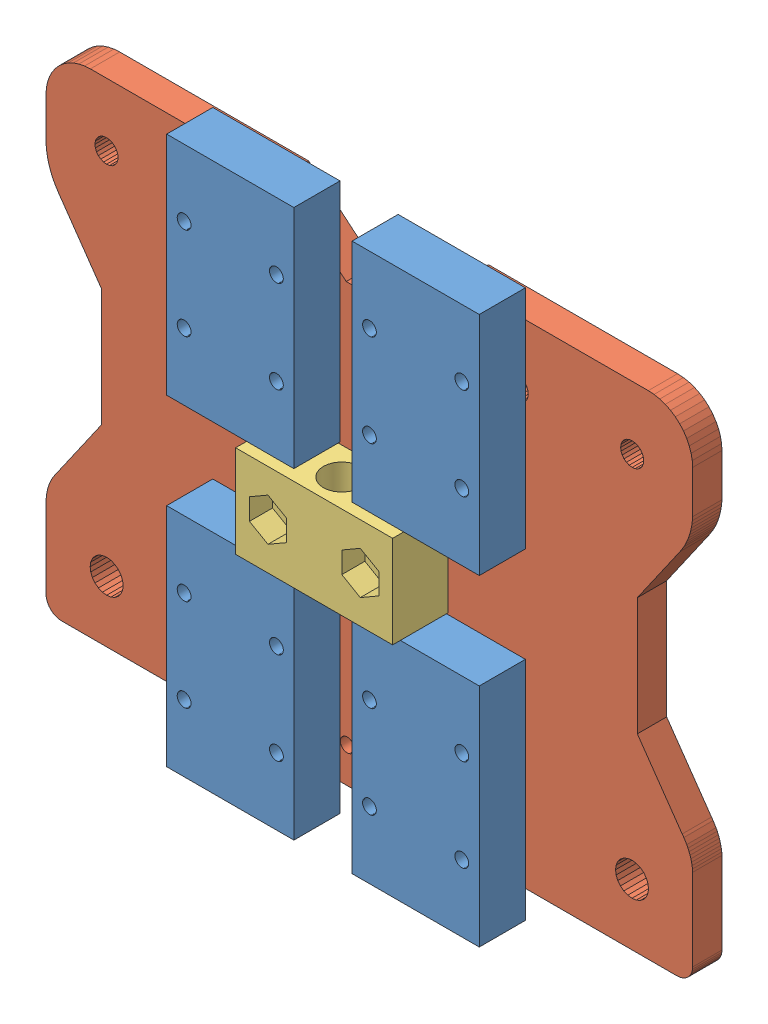
SolidWorks assembly Assem1, configuration Default. Lengths in mm.
Overall size (140.05 118.72 18.4).
6 component instances, 3 part files, 16 mates.
Components (placement in the parent):
- Mg12 block-1: Mg12 block [Default] at (164.5999 -6 6.6764) x (1 0 -0.000519) z (0.000519 0 1) size (27.56 49 10)
- for sliders-1: for sliders [Default] at (126.4849 583.1079 0.3462) x (0 -1 0) z (0.000519 0 1) size (106.72 140.05 6.35)
- Mg12 block-2: Mg12 block [Default] at (204.7487 -6 6.6556) x (1 0 -0.000519) z (0.000519 0 1) size (27.56 49 10)
- 8mm Acme Nut Block-1: 8mm Acme Nut Block [Default] at (198.5422 63.325 12.6588) x (1 0 -0.000519) z (0 -1 0) size (34 12 20)
- Mg12 block-3: Mg12 block [Default] at (164.5999 63.716 6.6693) size (27.56 49 10)
- Mg12 block-4: Mg12 block [Default] at (204.7487 63.716 6.6556) x (1 0 -0.000519) z (0.000519 0 1) size (27.56 49 10)
Mates (geometry in assembly coordinates):
- Coincident1: coincident anti-aligned: plane of for sliders-1 through (126.4882 0 6.6962) normal (0 -1 0); plane of assembly through (0 0 0) normal (0 1 0)
- Coincident2: coincident anti-aligned: plane of Mg12 block-1 through (164.5999 -6 6.6764) normal (-0.000519 0 -1); plane of for sliders-1 through (126.4882 583.1079 6.6962) normal (0.000519 0 1)
- Coincident3: coincident aligned: line of Mg12 block-1 through (178.3812 43 6.6693) axis (0 -1 0); line of for sliders-1 through (178.3812 93.8378 6.6693) axis (0 -1 0)
- Distance3: distance = 6 mm aligned: plane of Mg12 block-1 through (164.6051 -6 16.6764) normal (0 -1 0); plane of for sliders-1 through (126.4882 0 6.6962) normal (0 -1 0)
- Distance1: distance = 6 mm aligned: plane of for sliders-1 through (126.4882 0 6.6962) normal (0 -1 0); plane of Mg12 block-2 through (204.7539 -6 16.6556) normal (0 -1 0)
- Coincident6: coincident anti-aligned: plane of for sliders-1 through (126.4882 583.1079 6.6962) normal (0.000519 0 1); plane of Mg12 block-2 through (204.7487 -6 6.6556) normal (-0.000519 0 -1)
- Coincident7: coincident aligned: line of for sliders-1 through (218.5299 97.1079 6.6484) axis (0 -1 0); line of Mg12 block-2 through (218.5299 43 6.6484) axis (0 -1 0)
- Coincident8: coincident anti-aligned: plane of for sliders-1 through (126.4882 583.1079 6.6962) normal (0.000519 0 1); plane of 8mm Acme Nut Block-1 through (215.5391 43.325 6.65) normal (-0.000519 0 -1)
- Concentric1: concentric aligned: circle of for sliders-1; cylinder of 8mm Acme Nut Block-1 through (208.5391 53.325 6.6536) axis (0.000519 0 1) radius 2.55
- Parallel1: parallel aligned: plane of for sliders-1 through (126.4882 94.4986 6.6962) normal (0 1 0); plane of 8mm Acme Nut Block-1 through (198.5422 63.325 12.6588) normal (0 1 0)
- Coincident10: coincident: plane of for sliders-1 through (126.4882 583.1079 6.6962) normal (0.000519 0 1); plane of Mg12 block-4 through (204.7487 63.716 6.6556) normal (-0.000519 0 -1)
- Coincident11: coincident: line of for sliders-1 through (218.5299 97.1079 6.6484) axis (0 -1 0); line of Mg12 block-4 through (218.5299 112.716 6.6484) axis (0 -1 0)
- Coincident12: coincident: plane of for sliders-1 through (126.4882 583.1079 6.6962) normal (0.000519 0 1); line of Mg12 block-3 through (178.3812 112.716 6.6693) axis (0 -1 0)
- Coincident13: coincident: line of for sliders-1 through (178.3812 93.8378 6.6693) axis (0 -1 0); line of Mg12 block-3 through (178.3812 112.716 6.6693) axis (0 -1 0)
- Distance4: distance = 6 mm: plane of Mg12 block-3 through (164.5999 112.716 16.6693) normal (0 1 0); line of for sliders-1 through (138.093 106.716 0.3402) axis (1 0 -0.000519)
- Distance5: distance = 6 mm aligned: plane of Mg12 block-4 through (204.7539 112.716 16.6556) normal (0 1 0); plane of for sliders-1 through (126.4882 106.716 6.6962) normal (0 1 0)
